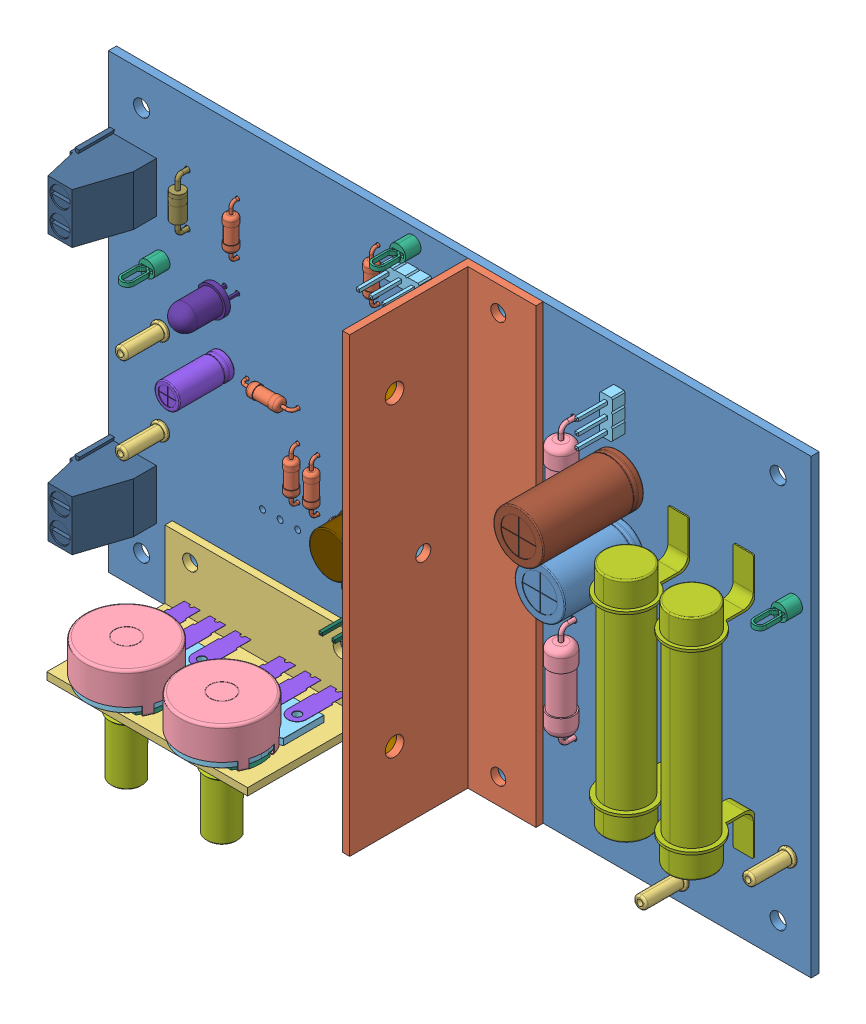
SolidWorks assembly amplif de putere, configuration Default. Lengths in mm.
Overall size (140.19 104.05 37.62).
96 component instances, 26 part files, 12 mates.
Components (placement in the parent):
- amplif de putere.step-1: amplif de putere.step [Default] at origin size (140.19 90 29.75)
  - C_Radial_D10.0mm_H16.0mm_P5.00mm.step-1: C_Radial_D10.0mm_H16.0mm_P5.00mm.step [Default] at (101.97 53 1.65) x (0 1 0) z (0 0 1) size (15 17.33 18)
    - SOLID.step-1: SOLID.step [Default] at origin size (15 17.33 18)
  - R_Axial_DIN0207_L6.3mm_D2.5mm_P10.16mm_Horizontal.step-1: R_Axial_DIN0207_L6.3mm_D2.5mm_P10.16mm_Horizontal.step [Default] at (37.72 30.92 1.65) x (0 1 0) z (0 0 1) size (10.76 2.5 5.69)
    - SOLID-0.step-1: SOLID-0.step [Default] at origin size (10.76 2.5 5.69)
  - CustomPinHeader.step-1: CustomPinHeader.step [Default] at (62.72 4.25 0.05) x (1 0 0) z (0 -1 0) size (3.4 9.9 3.4)
    - SOLID-1.step-1: SOLID-1.step [Default] at origin size (3.4 9.9 3.4)
  - R_Axial_DIN0516_L15.5mm_D5.0mm_P20.32mm_Horizontal.step-1: R_Axial_DIN0516_L15.5mm_D5.0mm_P20.32mm_Horizontal.step [Default] at (92.72 38.16 1.65) x (0 -1 0) z (0 0 1) size (21.12 5 8.39)
    - SOLID-2.step-1: SOLID-2.step [Default] at origin size (21.12 5 8.39)
  - R_Axial_DIN0516_L15.5mm_D5.0mm_P20.32mm_Horizontal.step-2: R_Axial_DIN0516_L15.5mm_D5.0mm_P20.32mm_Horizontal.step [Default] at (92.72 73 1.65) x (0 -1 0) z (0 0 1) size (21.12 5 8.39)
    - SOLID-2.step-1: SOLID-2.step [Default] at origin size (21.12 5 8.39)
  - CustomPinHeader.step-2: CustomPinHeader.step [Default] at (135.72 19 0.05) x (1 0 0) z (0 -1 0) size (3.4 9.9 3.4)
    - SOLID-1.step-1: SOLID-1.step [Default] at origin size (3.4 9.9 3.4)
  - R_Axial_DIN0207_L6.3mm_D2.5mm_P10.16mm_Horizontal.step-2: R_Axial_DIN0207_L6.3mm_D2.5mm_P10.16mm_Horizontal.step [Default] at (49.64 46 1.65) size (10.76 2.5 5.69)
    - SOLID-0.step-1: SOLID-0.step [Default] at origin size (10.76 2.5 5.69)
  - PinHeader_1x03_P2.54mm_Vertical.step-1: PinHeader_1x03_P2.54mm_Vertical.step [Default] at (101.72 81.525 1.65) size (2.54 7.62 11.54)
    - SOLID-3.step-1: SOLID-3.step [Default] at origin size (2.54 7.62 11.54)
  - CustomPinHeader.step-3: CustomPinHeader.step [Default] at (10.72 30 0.05) x (1 0 0) z (0 -1 0) size (3.4 9.9 3.4)
    - SOLID-1.step-1: SOLID-1.step [Default] at origin size (3.4 9.9 3.4)
  - 5013--3DModel-STEP-56544.step-1: 5013--3DModel-STEP-56544.step [Default] at (136.72 63 1.65) x (1 0 0) z (0 -1 0) size (3.17 11.68 3.17)
    - COMPOUND.step-1: COMPOUND.step [Default] at origin size (3.17 11.68 3.17)
  - power resistor.step-1: power resistor.step [Default] at (126.72 41.25 12.15) x (0 0 -1) z (0 -1 0) size (15.9 11.87 52.47)
    - SOLID-4.step-1: SOLID-4.step [Default] at origin size (15.9 11.87 52.47)
  - C_Radial_D5.0mm_H11.0mm_P2.00mm.step-1: C_Radial_D5.0mm_H11.0mm_P2.00mm.step [Default] at (21.72 47.25 1.65) size (7.5 8.67 13)
    - SOLID-5.step-1: SOLID-5.step [Default] at origin size (7.5 8.67 13)
  - R_Axial_DIN0207_L6.3mm_D2.5mm_P10.16mm_Horizontal.step-3: R_Axial_DIN0207_L6.3mm_D2.5mm_P10.16mm_Horizontal.step [Default] at (53.72 83.33 1.65) x (0 -1 0) z (0 0 1) size (10.76 2.5 5.69)
    - SOLID-0.step-1: SOLID-0.step [Default] at origin size (10.76 2.5 5.69)
  - 5013--3DModel-STEP-56544.step-2: 5013--3DModel-STEP-56544.step [Default] at (60.72 87 1.65) x (1 0 0) z (0 -1 0) size (3.17 11.68 3.17)
    - COMPOUND.step-1: COMPOUND.step [Default] at origin size (3.17 11.68 3.17)
  - R_Axial_DIN0207_L6.3mm_D2.5mm_P10.16mm_Horizontal.step-4: R_Axial_DIN0207_L6.3mm_D2.5mm_P10.16mm_Horizontal.step [Default] at (27.64 47.25 1.65) size (10.76 2.5 5.69)
    - SOLID-0.step-1: SOLID-0.step [Default] at origin size (10.76 2.5 5.69)
  - R_Axial_DIN0207_L6.3mm_D2.5mm_P10.16mm_Horizontal.step-5: R_Axial_DIN0207_L6.3mm_D2.5mm_P10.16mm_Horizontal.step [Default] at (25.72 77.33 1.65) x (0 -1 0) z (0 0 1) size (10.76 2.5 5.69)
    - SOLID-0.step-1: SOLID-0.step [Default] at origin size (10.76 2.5 5.69)
  - TO-220-3_Vertical.step-1: TO-220-3_Vertical.step [Default] at (68.45 17.08 1.65) x (0 -1 0) z (0 0 1) size (10.25 4.46 28.53)
    - SOLID-6.step-1: SOLID-6.step [Default] at origin size (10.25 4.46 28.53)
  - TerminalBlock_Phoenix_MKDS-1,5-2_1x02_P5.00mm_Horizontal.step-1: TerminalBlock_Phoenix_MKDS-1,5-2_1x02_P5.00mm_Horizontal.step [Default] at (4.415 20.75 1.65) x (0 -1 0) z (0 0 1) size (10.74 9.8 17.3)
    - SOLID-7.step-1: SOLID-7.step [Default] at origin size (10.74 9.8 17.3)
  - R_Axial_DIN0207_L6.3mm_D2.5mm_P10.16mm_Horizontal.step-6: R_Axial_DIN0207_L6.3mm_D2.5mm_P10.16mm_Horizontal.step [Default] at (103.72 26.92 1.65) x (0 1 0) z (0 0 1) size (10.76 2.5 5.69)
    - SOLID-0.step-1: SOLID-0.step [Default] at origin size (10.76 2.5 5.69)
  - 5013--3DModel-STEP-56544.step-3: 5013--3DModel-STEP-56544.step [Default] at (10.72 59.25 1.65) x (1 0 0) z (0 -1 0) size (3.17 11.68 3.17)
    - COMPOUND.step-1: COMPOUND.step [Default] at origin size (3.17 11.68 3.17)
  - C_Radial_D10.0mm_H20.0mm_P5.00mm.step-1: C_Radial_D10.0mm_H20.0mm_P5.00mm.step [Default] at (101.72 64.5 1.65) x (0 1 0) z (0 0 1) size (15 17.33 22)
    - SOLID-8.step-1: SOLID-8.step [Default] at origin size (15 17.33 22)
  - D_DO-41_SOD81_P10.16mm_Horizontal.step-1: D_DO-41_SOD81_P10.16mm_Horizontal.step [Default] at (15.72 77.33 1.65) x (0 -1 0) z (0 0 1) size (10.96 3.14 5.71)
    - SOLID-9.step-1: SOLID-9.step [Default] at origin size (10.96 3.14 5.71)
  - R_Axial_DIN0207_L6.3mm_D2.5mm_P10.16mm_Horizontal.step-7: R_Axial_DIN0207_L6.3mm_D2.5mm_P10.16mm_Horizontal.step [Default] at (53.64 60 1.65) size (10.76 2.5 5.69)
    - SOLID-0.step-1: SOLID-0.step [Default] at origin size (10.76 2.5 5.69)
  - C_Disc_D3.0mm_W2.0mm_P2.50mm.step-1: C_Disc_D3.0mm_W2.0mm_P2.50mm.step [Default] at (63.97 12.25 1.65) x (0 1 0) z (0 0 1) size (3.08 2 5.33)
    - SOLID-10.step-1: SOLID-10.step [Default] at origin size (3.08 2 5.33)
  - R_Axial_DIN0207_L6.3mm_D2.5mm_P10.16mm_Horizontal.step-8: R_Axial_DIN0207_L6.3mm_D2.5mm_P10.16mm_Horizontal.step [Default] at (63.8 65 1.65) x (-1 0 0) z (0 0 1) size (10.76 2.5 5.69)
    - SOLID-0.step-1: SOLID-0.step [Default] at origin size (10.76 2.5 5.69)
  - TO-126-3_Vertical.step-1: TO-126-3_Vertical.step [Default] at (69.6 47.54 1.65) x (0 -1 0) z (0 0 1) size (8 3.25 23.75)
    - SOLID-11.step-1: SOLID-11.step [Default] at origin size (8 3.25 23.75)
  - R_Axial_DIN0207_L6.3mm_D2.5mm_P10.16mm_Horizontal.step-9: R_Axial_DIN0207_L6.3mm_D2.5mm_P10.16mm_Horizontal.step [Default] at (41.72 41.08 1.65) x (0 -1 0) z (0 0 1) size (10.76 2.5 5.69)
    - SOLID-0.step-1: SOLID-0.step [Default] at origin size (10.76 2.5 5.69)
  - CustomPinHeader.step-4: CustomPinHeader.step [Default] at (114.22 4.25 0.05) x (1 0 0) z (0 -1 0) size (3.4 9.9 3.4)
    - SOLID-1.step-1: SOLID-1.step [Default] at origin size (3.4 9.9 3.4)
  - PinHeader_1x02_P2.54mm_Vertical.step-1: PinHeader_1x02_P2.54mm_Vertical.step [Default] at (50.72 19 1.65) x (0 1 0) z (0 0 1) size (2.54 5.08 11.54)
    - SOLID-12.step-1: SOLID-12.step [Default] at origin size (2.54 5.08 11.54)
  - C_Disc_D6.0mm_W2.5mm_P5.00mm.step-1: C_Disc_D6.0mm_W2.5mm_P5.00mm.step [Default] at (103.72 11.5 1.65) x (0 1 0) z (0 0 1) size (6 2.5 8.56)
    - SOLID-13.step-1: SOLID-13.step [Default] at origin size (6 2.5 8.56)
  - TerminalBlock_Phoenix_MKDS-1,5-2_1x02_P5.00mm_Horizontal.step-2: TerminalBlock_Phoenix_MKDS-1,5-2_1x02_P5.00mm_Horizontal.step [Default] at (4.415 73.75 1.65) x (0 -1 0) z (0 0 1) size (10.74 9.8 17.3)
    - SOLID-7.step-1: SOLID-7.step [Default] at origin size (10.74 9.8 17.3)
  - LED_D5.0mm.step-1: LED_D5.0mm.step [Default] at (23.1743 60.9813 1.65) size (5.4 6.76 14.1)
    - SOLID-14.step-1: SOLID-14.step [Default] at origin size (5.4 6.76 14.1)
  - PinHeader_1x03_P2.54mm_Vertical.step-2: PinHeader_1x03_P2.54mm_Vertical.step [Default] at (63.22 82 1.65) x (0 -1 0) z (0 0 1) size (2.54 7.62 11.54)
    - SOLID-3.step-1: SOLID-3.step [Default] at origin size (2.54 7.62 11.54)
  - power resistor.step-2: power resistor.step [Default] at (113.72 41.25 12.15) x (0 0 -1) z (0 -1 0) size (15.9 11.87 52.47)
    - SOLID-4.step-1: SOLID-4.step [Default] at origin size (15.9 11.87 52.47)
  - 5013--3DModel-STEP-56544.step-4: 5013--3DModel-STEP-56544.step [Default] at (60.695 76 1.65) x (1 0 0) z (0 -1 0) size (3.17 11.68 3.17)
    - COMPOUND.step-1: COMPOUND.step [Default] at origin size (3.17 11.68 3.17)
  - CustomPinHeader.step-5: CustomPinHeader.step [Default] at (10.72 47.25 0.05) x (1 0 0) z (0 -1 0) size (3.4 9.9 3.4)
    - SOLID-1.step-1: SOLID-1.step [Default] at origin size (3.4 9.9 3.4)
  - R_Axial_DIN0207_L6.3mm_D2.5mm_P10.16mm_Horizontal.step-10: R_Axial_DIN0207_L6.3mm_D2.5mm_P10.16mm_Horizontal.step [Default] at (46.64 23.25 1.65) size (10.76 2.5 5.69)
    - SOLID-0.step-1: SOLID-0.step [Default] at origin size (10.76 2.5 5.69)
  - C_Disc_D3.0mm_W2.0mm_P2.50mm.step-2: C_Disc_D3.0mm_W2.0mm_P2.50mm.step [Default] at (46.72 31 1.65) x (0 1 0) z (0 0 1) size (3.08 2 5.33)
    - SOLID-10.step-1: SOLID-10.step [Default] at origin size (3.08 2 5.33)
  - TO-39-3.step-1: TO-39-3.step [Default] at (55.72 34 1.65) x (0 1 0) z (0 0 1) size (9.92 10.16 16.5)
    - SOLID-15.step-1: SOLID-15.step [Default] at origin size (9.92 10.16 16.5)
  - TO-220-3_Vertical.step-2: TO-220-3_Vertical.step [Default] at (68.45 78 1.65) x (0 -1 0) z (0 0 1) size (10.25 4.46 28.53)
    - SOLID-6.step-1: SOLID-6.step [Default] at origin size (10.25 4.46 28.53)
  - amplif de putere PCB.step-1: amplif de putere PCB.step [Default] at origin size (140 90 1.6)
- radiator trans-1: radiator trans [Default] at (79.11 45 1.6) size (15 90 25)
- radiator pot-1: radiator pot [Default] at (32.72 7.75 1.6) x (-1 0 0) z (0 0 1) size (40 15 25)
- User Library-Potentiometer-4-1: User Library-Potentiometer-4 [-1] at (23.22 10.336 21.2) x (-1 0 0) z (0 0 1) size (16.64 24.38 28.19)
  - User Library-Potentiometer-4_Pot Base-1: User Library-Potentiometer-4_Pot Base [-1] at origin size (16.64 8.26 16.64)
  - User Library-Potentiometer-4_POT Board-1: User Library-Potentiometer-4_POT Board [-1] at (0 6.35 0) x (0 0 -1) z (1 0 0) size (20.32 1.53 15.75)
  - User Library-Potentiometer-4_POT PLATE 1-1: User Library-Potentiometer-4_POT PLATE 1 [Default] at (0 7.62 0) x (0 0 -1) z (0 1 0) size (9.03 15.32 3.73)
  - User Library-Potentiometer-4_POT shaft-1: User Library-Potentiometer-4_POT shaft [Default] at (0 6.35 0) x (-0.042361 0 0.999102) z (0 -1 0) size (14.96 14.96 18.29)
  - User Library-Potentiometer-4_POT wire connections-1: User Library-Potentiometer-4_POT wire connections [Default] at (0 6.35 0) x (0 0 1) z (0 -1 0) size (11.81 13.84 0.05)
- User Library-Potentiometer-4-2: User Library-Potentiometer-4 [-1] at (42.22 10.336 21.2) x (-1 0 0) z (0 0 1) size (16.64 24.38 28.19)
  - User Library-Potentiometer-4_Pot Base-1: User Library-Potentiometer-4_Pot Base [-1] at origin size (16.64 8.26 16.64)
  - User Library-Potentiometer-4_POT Board-1: User Library-Potentiometer-4_POT Board [-1] at (0 6.35 0) x (0 0 -1) z (1 0 0) size (20.32 1.53 15.75)
  - User Library-Potentiometer-4_POT PLATE 1-1: User Library-Potentiometer-4_POT PLATE 1 [Default] at (0 7.62 0) x (0 0 -1) z (0 1 0) size (9.03 15.32 3.73)
  - User Library-Potentiometer-4_POT shaft-1: User Library-Potentiometer-4_POT shaft [Default] at (0 6.35 0) x (-0.042361 0 0.999102) z (0 -1 0) size (14.96 14.96 18.29)
  - User Library-Potentiometer-4_POT wire connections-1: User Library-Potentiometer-4_POT wire connections [Default] at (0 6.35 0) x (0 0 1) z (0 -1 0) size (11.81 13.84 0.05)
Mates (geometry in assembly coordinates):
- Coincident1: coincident anti-aligned: plane of amplif de putere.step-1/amplif de putere PCB.step-1 through (70 45 1.6) normal (0 0 1); plane of radiator trans-1 through (79.11 45 1.6) normal (0 0 -1)
- Coincident2: coincident: plane of amplif de putere.step-1/amplif de putere PCB.step-1 through (140 0 0) normal (0 -1 0); line of radiator trans-1 through (73.06 0 3.05) axis (1 0 0)
- Tangent1: tangent: plane of assembly; face of amplif de putere.step-1/TO-220-3_Vertical.step-1/SOLID-6.step-1; plane of radiator trans-1 through (71.61 90 3.05) normal (-1 0 0)
- Concentric3: concentric aligned: circle of amplif de putere.step-1/amplif de putere PCB.step-1; cylinder of radiator pot-1 through (47.72 11.25 1.599) axis (0 0 1) radius 1.5
- Coincident5: coincident anti-aligned: plane of amplif de putere.step-1/amplif de putere PCB.step-1 through (70 45 1.6) normal (0 0 1); plane of radiator pot-1 through (32.72 7.75 1.6) normal (0 0 -1)
- Concentric4: concentric aligned: cylinder of amplif de putere.step-1/amplif de putere PCB.step-1 through (17.72 11.25 -0.8) axis (0 0 1) radius 1.6; cylinder of radiator pot-1 through (17.72 11.25 1.599) axis (0 0 1) radius 1.5
- Concentric5: concentric anti-aligned: cylinder of radiator pot-1 through (23.22 15.251 21.2) axis (0 -1 0) radius 3.5; cylinder of User Library-Potentiometer-4-1/User Library-Potentiometer-4_POT shaft-1 through (23.22 -14.048 21.2) axis (0 1 0) radius 3.048
- Parallel3: parallel aligned: plane of radiator pot-1 through (12.72 15.25 3.05) normal (-1 0 0); plane of User Library-Potentiometer-4-1/User Library-Potentiometer-4_POT Board-1 through (15.346 2.716 8.754) normal (-1 0 0)
- Coincident6: coincident anti-aligned: plane of radiator pot-1 through (52.72 1.7 26.6) normal (0 1 0); plane of User Library-Potentiometer-4-1/User Library-Potentiometer-4_POT PLATE 1-1 through (23.22 1.7 21.2) normal (0 -1 0)
- Concentric6: concentric: cylinder of radiator pot-1 through (42.22 15.251 21.2) axis (0 -1 0) radius 3.5; cylinder of User Library-Potentiometer-4-2/User Library-Potentiometer-4_POT shaft-1 through (42.22 -14.048 21.2) axis (0 1 0) radius 3.048
- Coincident7: coincident: plane of radiator pot-1 through (52.72 1.7 26.6) normal (0 1 0); plane of User Library-Potentiometer-4-2/User Library-Potentiometer-4_POT PLATE 1-1 through (42.22 1.7 21.2) normal (0 -1 0)
- Parallel4: parallel aligned: plane of radiator pot-1 through (52.72 15.25 3.05) normal (1 0 0); plane of User Library-Potentiometer-4-2/User Library-Potentiometer-4_POT Board-1
